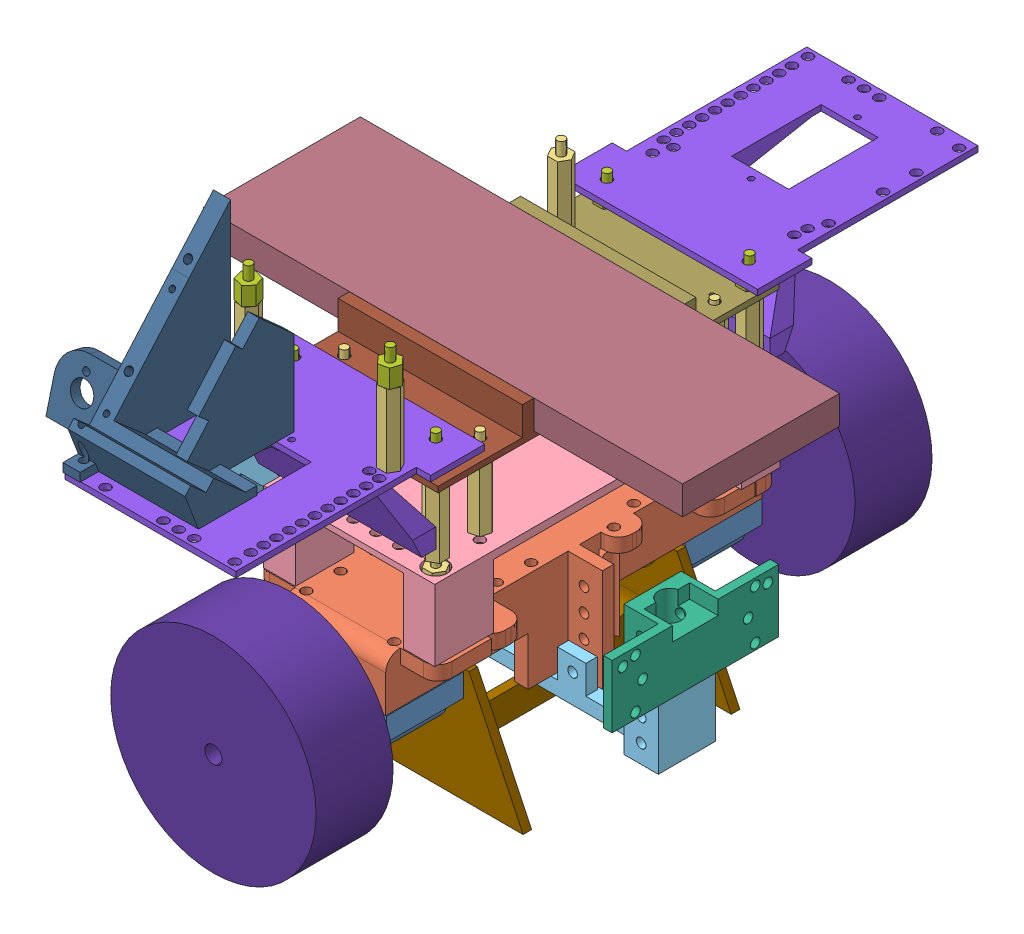
SolidWorks assembly Assemblage_idir_01, configuration Défaut. Lengths in mm.
Overall size (180.33 181.95 261.59).
39 component instances, 17 part files, 85 mates.
Components (placement in the parent):
- Pièce2b-1: Pièce2b [Défaut] at (-3.667 32.9905 263.0949) x (1 0 0) z (0 0 -1) size (37.12 18 27)
- Pièce2b-2: Pièce2b [Défaut] at (-3.9871 32.9905 131.0949) x (-1 0 0) z (0 0 1) size (37.12 18 27)
- Pièce1c-1: Pièce1c [Défaut] at (-3.827 32.9905 131.0949) size (72.97 36 132.85)
- exagone1-6: exagone1 [Défaut] at (-28.0508 79.4392 234.999) x (0.341411 0 -0.939914) z (0 1 0) size (7.1 6.15 30.2)
- exagone1-7: exagone1 [Défaut] at (-27.2527 77.9905 159.7058) x (0.97328 0 -0.229621) z (0 1 0) size (7.1 6.15 30.2)
- exagone1-8: exagone1 [Défaut] at (20.393 77.9905 153.5574) x (1 0 0) z (0 1 0) size (7.1 6.15 30.2)
- exagone1-9: exagone1 [Défaut] at (20.6941 79.4392 236.1549) x (-0.271527 0 0.962431) z (0 1 0) size (7.1 6.15 30.2)
- exagone1-11: exagone1 [Défaut] at (-27.2527 105.4905 159.7058) x (1 0 0.000039) z (0 1 0) size (7.1 6.15 30.2)
- support_batterie_portable1-1: support_batterie_portable1 [Défaut] at (10.2075 50.9905 203.6226) x (1 0 0) z (0 1 0) size (60 121.05 25)
- exagone1-12: exagone1 [Défaut] at (21.173 50.9905 142.0949) x (1 0 0) z (0 1 0) size (7.1 6.15 30.2)
- exagone1-13: exagone1 [Défaut] at (-28.827 50.9905 142.0949) x (0.791864 0 -0.610698) z (0 1 0) size (7.1 6.15 30.2)
- exagone1-14: exagone1 [Défaut] at (-28.827 50.9905 252.0949) x (1 0 0) z (0 1 0) size (7.1 6.15 30.2)
- exagone1-15: exagone1 [Défaut] at (21.173 50.9905 252.0949) x (1 0 0) z (0 1 0) size (7.1 6.15 30.2)
- stabilizer2-1: stabilizer2 [Défaut] at (-4.2222 13.9905 199.0949) x (1 0 0) z (0 -1 0) size (120.8 20 21)
- support_sensor_01-1: support_sensor_01 [Défaut] at (44.1778 32.671 209.0949) x (0 0 -1) z (1 0 0) size (58.42 22 15)
- exagone1-16: exagone1 [Défaut] at (21.173 79.4392 252.0949) x (-0.008292 0 0.999966) z (0 1 0) size (7.1 6.15 30.2)
- exagone1-17: exagone1 [Défaut] at (-28.827 79.4392 252.0949) x (0.990134 0 0.140123) z (0 1 0) size (7.1 6.15 30.2)
- exagone1-18: exagone1 [Défaut] at (-28.827 77.9905 142.0949) x (1 0 0) z (0 1 0) size (7.1 6.15 30.2)
- exagone1-19: exagone1 [Défaut] at (21.173 77.9905 142.0949) x (1 0 0) z (0 1 0) size (7.1 6.15 30.2)
- exagone_6_5-1: exagone_6_5 [Défaut] at (-28.827 105.1811 142.0949) x (1 0 0) z (0 1 0) size (7.1 6.15 11.2)
- exagone_6_5-2: exagone_6_5 [Défaut] at (21.173 105.1811 142.0949) x (1 0 0) z (0 1 0) size (7.1 6.15 11.2)
- exagone_6_5-3: exagone_6_5 [Défaut] at (21.173 106.3269 252.0949) x (0.994038 0 0.109035) z (0 1 0) size (7.1 6.15 11.2)
- exagone_6_5-4: exagone_6_5 [Défaut] at (-28.827 106.3269 252.0949) x (0.996071 0 0.08856) z (0 1 0) size (7.1 6.15 11.2)
- support_experiment_02-1: support_experiment_02 [Défaut] at (21.173 114.8269 252.0949) x (0 0 -1) z (0 -1 0) size (82.27 70 30)
- support_all_robot01-1: support_all_robot01 [Défaut] at (-4.727 12.9905 197.0949) x (0 0 -1) z (1 0 0) size (76 40 76)
- exagone1-20: exagone1 [Défaut] at (-28.527 114.8269 268.0949) x (1 0 0) z (0 1 0) size (7.1 6.15 30.2)
- exagone1-21: exagone1 [Défaut] at (21.173 114.8269 268.0949) x (1 0 0) z (0 1 0) size (7.1 6.15 30.2)
- exagone_6_5-5: exagone_6_5 [Défaut] at (21.173 140.3269 268.0949) x (0.977348 0 -0.211637) z (0 1 0) size (7.1 6.15 11.2)
- exagone_6_5-6: exagone_6_5 [Défaut] at (-28.527 140.3269 268.0949) x (0.971301 0 0.237855) z (0 1 0) size (7.1 6.15 11.2)
- support_ecran_idir_01-1: support_ecran_idir_01 [Défaut] at (20.7866 114.8269 253.1451) x (0 0 1) z (0 1 0) size (82.27 80 59.42)
- support_breadboard_droit_01-2: support_breadboard_droit_01 [Défaut] at (30.9479 106.9392 216.3038) x (1 0 0) z (0 1 0) size (64.63 40 12)
- support_breadboard_gouche_01-1: support_breadboard_gouche_01 [Défaut] at (-57.2792 106.9392 107.5569) x (1 0 0) z (0 1 0) size (61.5 40 12)
- support_experiment_02-3: support_experiment_02 [Défaut] at (-28.827 113.6811 142.0949) x (0 0 1) z (0 -1 0) size (82.27 70 30)
- breadboard01-1: breadboard01 [Défaut] at (0.3062 106.9392 366.3401) x (1 0 0) z (0 1 0) size (168 55 10)
- support_line_detector_01-1: support_line_detector_01 [Défaut] at (-100.1222 11.1165 199.0949) x (0 0 1) z (0 1 0) size (31 25 16)
- support_li_detector_union_01-1: support_li_detector_union_01 [Défaut] at (-70.6222 39.9905 199.0949) x (0 0 1) z (0 1 0) size (20 40 10)
- support_sphere_01-1: support_sphere_01 [Défaut] at (-64.6222 2.8362 199.0949) x (0 0 -1) z (0 1 0) size (12 22 19.2)
- pneu_01-1: pneu_01 [Défaut] at (-3.827 32.9905 89.0949) x (0.990128 -0.140168 0) z (0 0 1) size (72 72 27)
- pneu_01-2: pneu_01 [Défaut] at (-3.827 32.9905 278.0949) size (72 72 27)
Mates (geometry in assembly coordinates):
- Coaxiale1: concentric anti-aligned: cylinder of Pièce2b-1 through (-19.227 32.9905 245.0949) axis (0 -1 0) radius 1.7; cylinder of Pièce1c-1 through (-19.227 32.9905 245.0949) axis (0 1 0) radius 1.7
- Parallèle1: parallel anti-aligned: cylinder of Pièce2b-1 through (11.8931 32.9905 257.0949) axis (0 -1 0) radius 1.7; cylinder of Pièce1c-1 through (11.573 32.9905 257.0949) axis (0 1 0) radius 1.7
- Coaxiale3: concentric anti-aligned: cylinder of Pièce2b-2 through (11.573 32.9905 137.0949) axis (0 -1 0) radius 1.7; cylinder of Pièce1c-1 through (11.573 32.9905 137.0949) axis (0 1 0) radius 1.7
- Parallèle2: parallel anti-aligned: cylinder of Pièce2b-2 through (-19.5472 32.9905 137.0949) axis (0 -1 0) radius 1.7; cylinder of Pièce1c-1 through (-19.227 32.9905 137.0949) axis (0 1 0) radius 1.7
- Coïncidente1: coincident anti-aligned: plane of Pièce2b-2 through (8.573 32.9905 158.0949) normal (0 1 0); plane of Pièce1c-1 through (-16.227 32.9905 263.0949) normal (0 -1 0)
- Coïncidente2: coincident anti-aligned: plane of Pièce2b-1 through (8.8931 32.9905 236.0949) normal (0 1 0); plane of Pièce1c-1 through (-16.227 32.9905 263.0949) normal (0 -1 0)
- Coaxiale28: concentric aligned: cylinder of exagone1-7 through (-27.2527 108.1905 159.7058) axis (0 -1 0) radius 1.385; cylinder of exagone1-11 through (-27.2527 110.1905 159.7058) axis (0 -1 0) radius 1.35
- Coïncidente35: coincident anti-aligned: plane of Pièce1c-1 through (-22.227 50.9905 263.0949) normal (0 1 0); plane of support_batterie_portable1-1 through (10.2075 50.9905 203.6226) normal (0 -1 0)
- Coïncidente37: coincident anti-aligned: plane of Pièce1c-1 through (-22.227 50.9905 263.0949) normal (0 1 0); plane of exagone1-12 through (21.173 50.9905 142.0949) normal (0 -1 0)
- Coaxiale29: concentric anti-aligned: cylinder of Pièce1c-1 through (21.173 35.9905 142.0949) axis (0 1 0) radius 1.7; cylinder of exagone1-12 through (21.173 55.6905 142.0949) axis (0 -1 0) radius 1.35
- Coaxiale32: concentric anti-aligned: cylinder of Pièce1c-1 through (21.173 35.9905 142.0949) axis (0 1 0) radius 1.7; cylinder of support_batterie_portable1-1 through (21.173 75.9905 142.0949) axis (0 -1 0) radius 4
- Coaxiale33: concentric anti-aligned: cylinder of Pièce1c-1 through (-28.827 35.9905 142.0949) axis (0 1 0) radius 1.7; circle of exagone1-13
- Coïncidente38: coincident anti-aligned: plane of Pièce1c-1 through (-22.227 50.9905 263.0949) normal (0 1 0); plane of exagone1-13 through (-28.827 50.9905 142.0949) normal (0 -1 0)
- Coaxiale34: concentric anti-aligned: cylinder of Pièce1c-1 through (-28.827 35.9905 252.0949) axis (0 1 0) radius 1.7; cylinder of exagone1-14 through (-28.827 55.6905 252.0949) axis (0 -1 0) radius 1.35
- Coïncidente39: coincident anti-aligned: plane of Pièce1c-1 through (-22.227 50.9905 263.0949) normal (0 1 0); plane of exagone1-14 through (-28.827 50.9905 252.0949) normal (0 -1 0)
- Coïncidente40: coincident anti-aligned: plane of Pièce1c-1 through (-22.227 50.9905 263.0949) normal (0 1 0); plane of exagone1-15 through (21.173 50.9905 252.0949) normal (0 -1 0)
- Coaxiale35: concentric anti-aligned: cylinder of Pièce1c-1 through (21.173 35.9905 252.0949) axis (0 1 0) radius 1.7; cylinder of exagone1-15 through (21.173 55.6905 252.0949) axis (0 -1 0) radius 1.35
- Coaxiale37: concentric aligned: cylinder of support_batterie_portable1-1 through (21.173 75.9905 252.0949) axis (0 -1 0) radius 4; cylinder of exagone1-15 through (21.173 81.1905 252.0949) axis (0 -1 0) radius 1.385
- Coaxiale40: concentric anti-aligned: cylinder of Pièce1c-1 through (20.393 42.9905 153.5574) axis (0 1 0) radius 1.7; cylinder of exagone1-8 through (20.393 82.6905 153.5574) axis (0 -1 0) radius 1.35
- Distance2: distance = 2 mm anti-aligned: plane of exagone1-7 through (-27.2527 77.9905 159.7058) normal (0 -1 0); plane of support_batterie_portable1-1 through (10.2075 75.9905 203.6226) normal (0 1 0)
- Coaxiale48: concentric aligned: cylinder of Pièce1c-1 through (20.1278 18.9905 187.0949) axis (0 0 1) radius 1.7; cylinder of stabilizer2-1 through (20.1278 18.9905 193.0949) axis (0 0 1) radius 1.7
- Parallèle16: parallel anti-aligned: plane of Pièce1c-1 through (-3.827 15.9905 131.0949) normal (0 -1 0); plane of stabilizer2-1 through (-4.2222 13.9905 199.0949) normal (0 1 0)
- Coïncidente57: coincident anti-aligned: plane of Pièce1c-1 through (26.573 14.9905 199.0949) normal (0 0 1); plane of stabilizer2-1 through (14.7778 23.9905 199.0949) normal (0 0 -1)
- Coaxiale49: concentric aligned: cylinder of stabilizer2-1 through (50.1778 5.9905 199.0949) axis (0 1 0) radius 4; cylinder of support_sensor_01-1 through (50.1778 28.671 199.0949) axis (0 1 0) radius 4
- Coïncidente58: coincident aligned: plane of stabilizer2-1 through (44.1778 8.9905 209.0949) normal (-1 0 0); plane of support_sensor_01-1 through (44.1778 32.671 209.0949) normal (-1 0 0)
- Coaxiale54: concentric aligned: cylinder of exagone1-9 through (20.6941 84.1392 236.1549) axis (0 -1 0) radius 1.35; cylinder of support_batterie_portable1-1 through (20.6941 75.9905 236.1549) axis (0 -1 0) radius 1.7
- Coaxiale55: concentric aligned: cylinder of exagone1-15 through (21.173 81.1905 252.0949) axis (0 -1 0) radius 1.385; cylinder of exagone1-16 through (21.173 84.1392 252.0949) axis (0 -1 0) radius 1.35
- Coaxiale56: concentric aligned: cylinder of exagone1-14 through (-28.827 81.1905 252.0949) axis (0 -1 0) radius 1.385; cylinder of exagone1-17 through (-28.827 84.1392 252.0949) axis (0 -1 0) radius 1.35
- Coaxiale57: concentric aligned: cylinder of exagone1-13 through (-28.827 81.1905 142.0949) axis (0 -1 0) radius 1.385; cylinder of exagone1-18 through (-28.827 82.6905 142.0949) axis (0 -1 0) radius 1.35
- Coaxiale58: concentric aligned: cylinder of exagone1-12 through (21.173 81.1905 142.0949) axis (0 -1 0) radius 1.385; cylinder of exagone1-19 through (21.173 82.6905 142.0949) axis (0 -1 0) radius 1.35
- Coaxiale60: concentric aligned: cylinder of exagone1-19 through (21.173 108.1905 142.0949) axis (0 -1 0) radius 1.385; cylinder of exagone_6_5-2 through (21.173 109.8811 142.0949) axis (0 -1 0) radius 1.35
- Coaxiale61: concentric aligned: cylinder of exagone1-18 through (-28.827 108.1905 142.0949) axis (0 -1 0) radius 1.385; cylinder of exagone_6_5-1 through (-28.827 109.8811 142.0949) axis (0 -1 0) radius 1.35
- Coaxiale67: concentric aligned: cylinder of exagone1-16 through (21.173 109.6392 252.0949) axis (0 -1 0) radius 1.385; cylinder of exagone_6_5-3 through (21.173 111.0269 252.0949) axis (0 -1 0) radius 1.35
- Coaxiale68: concentric aligned: cylinder of exagone1-17 through (-28.827 109.6392 252.0949) axis (0 -1 0) radius 1.385; cylinder of exagone_6_5-4 through (-28.827 111.0269 252.0949) axis (0 -1 0) radius 1.35
- Distance5: distance = 1 mm anti-aligned: plane of support_all_robot01-1 through (-3.227 32.9905 235.0949) normal (0 0 1); plane of Pièce2b-1 through (-3.667 32.9905 236.0949) normal (0 0 -1)
- Coïncidente81: coincident anti-aligned: plane of Pièce1c-1 through (-16.227 32.9905 263.0949) normal (0 -1 0); plane of support_all_robot01-1 through (-16.227 32.9905 235.0949) normal (0 1 0)
- Distance6: distance = 0 mm: line of support_all_robot01-1 through (-22.227 32.9905 235.0949) axis (0 0 -1); line of Pièce1c-1 through (-22.227 32.9905 263.0949) axis (0 0 -1)
- Coaxiale69: concentric anti-aligned: cylinder of exagone_6_5-3 through (21.173 117.5269 252.0949) axis (0 -1 0) radius 1.385; cylinder of support_experiment_02-1 through (21.173 112.8269 252.0949) axis (0 1 0) radius 1.7
- Coïncidente82: coincident anti-aligned: plane of exagone_6_5-3 through (21.173 112.8269 252.0949) normal (0 1 0); plane of support_experiment_02-1 through (21.173 112.8269 252.0949) normal (0 -1 0)
- Coaxiale70: concentric anti-aligned: cylinder of support_experiment_02-1 through (-28.527 112.8269 268.0949) axis (0 1 0) radius 1.7; cylinder of exagone1-20 through (-28.527 119.5269 268.0949) axis (0 -1 0) radius 1.35
- Coïncidente83: coincident anti-aligned: plane of support_experiment_02-1 through (21.173 114.8269 252.0949) normal (0 1 0); plane of exagone1-20 through (-28.527 114.8269 268.0949) normal (0 -1 0)
- Coaxiale71: concentric anti-aligned: cylinder of support_experiment_02-1 through (21.173 112.8269 268.0949) axis (0 1 0) radius 1.7; cylinder of exagone1-21 through (21.173 119.5269 268.0949) axis (0 -1 0) radius 1.35
- Coïncidente84: coincident anti-aligned: plane of support_experiment_02-1 through (21.173 114.8269 252.0949) normal (0 1 0); plane of exagone1-21 through (21.173 114.8269 268.0949) normal (0 -1 0)
- Coaxiale73: concentric aligned: cylinder of exagone1-21 through (21.173 145.0269 268.0949) axis (0 -1 0) radius 1.385; cylinder of exagone_6_5-5 through (21.173 145.0269 268.0949) axis (0 -1 0) radius 1.35
- Coïncidente86: coincident anti-aligned: plane of exagone1-21 through (21.173 140.3269 268.0949) normal (0 1 0); plane of exagone_6_5-5 through (21.173 140.3269 268.0949) normal (0 -1 0)
- Coaxiale74: concentric aligned: cylinder of exagone1-20 through (-28.527 145.0269 268.0949) axis (0 -1 0) radius 1.385; cylinder of exagone_6_5-6 through (-28.527 145.0269 268.0949) axis (0 -1 0) radius 1.35
- Coïncidente87: coincident anti-aligned: plane of exagone1-20 through (-28.527 140.3269 268.0949) normal (0 1 0); plane of exagone_6_5-6 through (-28.527 140.3269 268.0949) normal (0 -1 0)
- Parallèle23: parallel: plane of support_experiment_02-1 through (26.323 112.8269 327.3634) normal (0 0 1); plane of support_ecran_idir_01-1 through (-34.0634 117.8269 274.8377) normal (0 0 -1)
- Coaxiale79: concentric: cylinder of support_experiment_02-1 through (-31.0634 112.8269 323.3429) axis (0 1 0) radius 1.7; cylinder of support_ecran_idir_01-1 through (-31.0634 132.8269 323.3429) axis (0 -1 0) radius 1.4
- Coïncidente89: coincident: plane of support_experiment_02-1 through (21.173 114.8269 252.0949) normal (0 1 0); plane of support_ecran_idir_01-1 through (20.7866 114.8269 253.1451) normal (0 -1 0)
- Coïncidente90: coincident aligned: plane of exagone1-6 through (-28.0508 79.4392 234.999) normal (0 -1 0); plane of exagone1-9 through (20.6941 79.4392 236.1549) normal (0 -1 0)
- Coïncidente101: coincident anti-aligned: plane of exagone_6_5-4 through (-28.827 112.8269 252.0949) normal (0 1 0); plane of support_experiment_02-1 through (21.173 112.8269 252.0949) normal (0 -1 0)
- Coaxiale90: concentric anti-aligned: cylinder of exagone1-8 through (20.393 108.1905 153.5574) axis (0 -1 0) radius 1.385; cylinder of support_breadboard_gouche_01-1 through (20.393 104.9392 153.5574) axis (0 1 0) radius 1.6804
- Coaxiale91: concentric anti-aligned: cylinder of exagone1-7 through (-27.2527 108.1905 159.7058) axis (0 -1 0) radius 1.385; cylinder of support_breadboard_gouche_01-1 through (-27.2527 104.9392 159.7058) axis (0 1 0) radius 1.6804
- Parallèle26: parallel aligned: cylinder of exagone1-7 through (-27.2527 82.6905 159.7058) axis (0 -1 0) radius 1.35; cylinder of support_batterie_portable1-1 through (-27.5059 75.9905 159.7749) axis (0 -1 0) radius 1.7
- Parallèle27: parallel aligned: plane of support_batterie_portable1-1 through (-33.6765 75.9905 136.5694) normal (0 0 -1); plane of support_breadboard_gouche_01-1 through (25.9226 104.9392 136.422) normal (0 0 -1)
- Coaxiale93: concentric anti-aligned: cylinder of exagone_6_5-1 through (-28.827 116.3811 142.0949) axis (0 -1 0) radius 1.385; cylinder of support_experiment_02-3 through (-28.827 111.6811 142.0949) axis (0 1 0) radius 1.7
- Parallèle28: parallel anti-aligned: plane of support_breadboard_gouche_01-1 through (25.9226 104.9392 136.422) normal (0 0 -1); plane of support_experiment_02-3 through (-38.977 111.6811 149.0949) normal (0 0 1)
- Coïncidente102: coincident anti-aligned: plane of exagone_6_5-1 through (-28.827 111.6811 142.0949) normal (0 1 0); plane of support_experiment_02-3 through (-28.827 111.6811 142.0949) normal (0 -1 0)
- Coïncidente103: coincident anti-aligned: plane of exagone_6_5-2 through (21.173 111.6811 142.0949) normal (0 1 0); plane of support_experiment_02-3 through (-28.827 111.6811 142.0949) normal (0 -1 0)
- Parallèle29: parallel anti-aligned: plane of support_batterie_portable1-1 through (10.2075 75.9905 203.6226) normal (0 1 0); plane of breadboard01-1 through (0.3062 106.9392 366.3401) normal (0 -1 0)
- Parallèle30: parallel aligned: plane of support_batterie_portable1-1 through (-33.6765 75.9905 136.5694) normal (-1 0 0); plane of breadboard01-1 through (-87.7903 116.9392 169.6039) normal (-1 0 0)
- Coaxiale94: concentric anti-aligned: cylinder of exagone1-9 through (20.6941 109.6392 236.1549) axis (0 -1 0) radius 1.385; cylinder of support_breadboard_droit_01-2 through (20.6941 104.9392 236.1549) axis (0 1 0) radius 1.7192
- Coaxiale95: concentric anti-aligned: cylinder of exagone1-6 through (-28.0508 109.6392 234.999) axis (0 -1 0) radius 1.385; cylinder of support_breadboard_droit_01-2 through (-28.0508 104.9392 234.999) axis (0 1 0) radius 1.7192
- Coïncidente104: coincident anti-aligned: plane of exagone1-6 through (-28.0508 104.9392 234.999) normal (0 1 0); plane of support_breadboard_droit_01-2 through (30.9479 104.9392 216.3038) normal (0 -1 0)
- Parallèle31: parallel aligned: cylinder of exagone1-6 through (-28.0508 84.1392 234.999) axis (0 -1 0) radius 1.35; cylinder of support_batterie_portable1-1 through (-27.5059 75.9905 235.0149) axis (0 -1 0) radius 1.7
- Parallèle32: parallel aligned: plane of support_batterie_portable1-1 through (-33.6765 75.9905 257.6204) normal (0 0 1); plane of support_breadboard_droit_01-2 through (-36.566 104.9392 258.2061) normal (0 0 1)
- Coïncidente105: coincident anti-aligned: plane of exagone1-17 through (-28.827 104.9392 252.0949) normal (0 1 0); plane of support_breadboard_droit_01-2 through (30.9479 104.9392 216.3038) normal (0 -1 0)
- Coïncidente106: coincident anti-aligned: plane of exagone1-16 through (21.173 104.9392 252.0949) normal (0 1 0); plane of support_breadboard_droit_01-2 through (30.9479 104.9392 216.3038) normal (0 -1 0)
- Coïncidente107: coincident anti-aligned: plane of support_breadboard_droit_01-2 through (30.9479 106.9392 216.3038) normal (0 1 0); plane of breadboard01-1 through (0.3062 106.9392 366.3401) normal (0 -1 0)
- Coïncidente108: coincident anti-aligned: plane of support_breadboard_gouche_01-1 through (-57.2792 106.9392 107.5569) normal (0 1 0); plane of breadboard01-1 through (0.3062 106.9392 366.3401) normal (0 -1 0)
- Parallèle33: parallel anti-aligned: plane of stabilizer2-1 through (-64.6222 8.9905 195.0949) normal (-1 0 0); plane of support_line_detector_01-1 through (-75.1222 11.1165 199.0949) normal (1 0 0)
- Parallèle34: parallel aligned: plane of stabilizer2-1 through (-4.2222 29.9905 199.0949) normal (0 1 0); plane of support_line_detector_01-1 through (-100.1222 27.1165 199.0949) normal (0 1 0)
- Coaxiale96: concentric anti-aligned: cylinder of stabilizer2-1 through (-58.6222 5.9905 199.0949) axis (0 1 0) radius 4; cylinder of support_li_detector_union_01-1 through (-58.6222 49.9905 199.0949) axis (0 -1 0) radius 3.9741
- Coaxiale97: concentric anti-aligned: cylinder of support_line_detector_01-1 through (-82.6222 12.1165 199.0949) axis (0 1 0) radius 4; cylinder of support_li_detector_union_01-1 through (-82.6222 49.9905 199.0949) axis (0 -1 0) radius 3.9741
- Parallèle35: parallel anti-aligned: plane of stabilizer2-1 through (-64.6222 8.9905 195.0949) normal (-1 0 0); plane of support_li_detector_union_01-1 through (-50.6222 49.9905 189.0949) normal (1 0 0)
- Distance9: distance = 10 mm anti-aligned: plane of stabilizer2-1 through (-4.2222 29.9905 199.0949) normal (0 1 0); plane of support_li_detector_union_01-1 through (-70.6222 39.9905 199.0949) normal (0 -1 0)
- Coaxiale98: concentric aligned: cylinder of stabilizer2-1 through (-58.6222 5.9905 199.0949) axis (0 1 0) radius 4; cylinder of support_sphere_01-1 through (-58.6222 -1.1638 199.0949) axis (0 1 0) radius 3.9
- Parallèle36: parallel anti-aligned: plane of stabilizer2-1 through (-64.6222 8.9905 195.0949) normal (-1 0 0); plane of support_sphere_01-1 through (-52.6222 8.8362 205.0949) normal (1 0 0)
- Coaxiale99: concentric anti-aligned: cylinder of Pièce1c-1 through (-3.827 32.9905 263.0949) axis (0 0 -1) radius 12.4; cylinder of pneu_01-1 through (-3.827 32.9905 89.0949) axis (0 0 1) radius 3
- Distance7: distance = 15 mm anti-aligned: plane of pneu_01-1 through (-3.827 32.9905 116.0949) normal (0 0 1); plane of Pièce1c-1 through (-3.827 32.9905 131.0949) normal (0 0 -1)
- Coaxiale100: concentric anti-aligned: cylinder of Pièce1c-1 through (-3.827 32.9905 263.0949) axis (0 0 -1) radius 12.4; cylinder of pneu_01-2 through (-3.827 32.9905 278.0949) axis (0 0 1) radius 3
- Distance8: distance = 15 mm anti-aligned: plane of Pièce1c-1 through (-3.827 32.9905 263.0949) normal (0 0 1); plane of pneu_01-2 through (-3.827 32.9905 278.0949) normal (0 0 -1)
- Parallèle38: parallel anti-aligned: plane of support_experiment_02-1 through (31.323 112.8269 245.0949) normal (0 0 -1); plane of support_breadboard_droit_01-2 through (-36.566 104.9392 258.2061) normal (0 0 1)
- Coaxiale102: concentric anti-aligned: cylinder of support_experiment_02-1 through (-31.0634 112.8269 277.575) axis (0 1 0) radius 1.7; cylinder of support_ecran_idir_01-1 through (-31.0634 132.8269 277.575) axis (0 -1 0) radius 1.4
